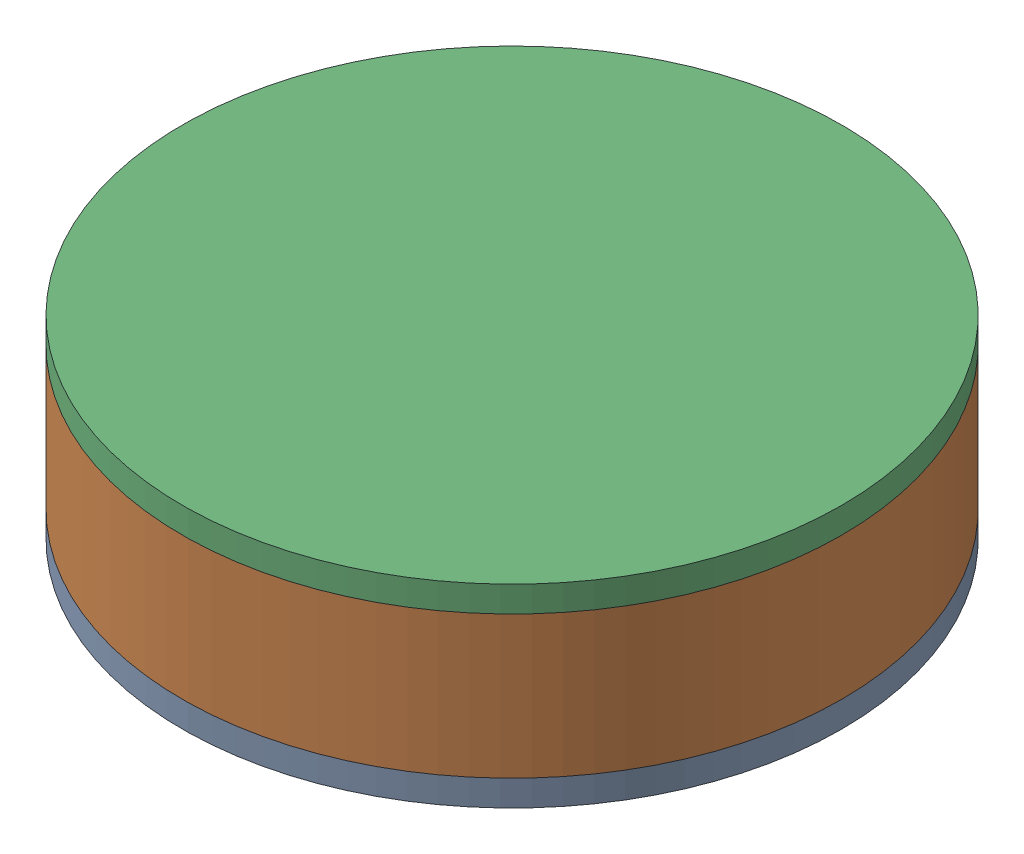
SolidWorks assembly Tip Mass, configuration Default. Lengths in mm.
Overall size (51 15 51).
3 component instances, 3 part files, 4 mates.
Components (placement in the parent):
- Tip Mass Bottom Plate (1)-1: Tip Mass Bottom Plate (1) [Default] at (20.4018 24.2669 38.6628) x (1 0 0) z (0 1 0) size (51 51 4)
- Tip Mass Side Wall (1)-1: Tip Mass Side Wall (1) [Default] at (20.4018 37.2669 38.6628) x (1 0 0) z (0 -1 0) size (51 51 11)
- Tip Mass Top Plate (1)-1: Tip Mass Top Plate (1) [Default] at (20.4018 39.2669 38.6628) x (1 0 0) z (0 -1 0) size (51 51 4)
Mates (geometry in assembly coordinates):
- Coincident1: coincident anti-aligned: plane of Tip Mass Bottom Plate-1 through (20.4018 26.2669 38.6628) normal (0 1 0); plane of Tip Mass Side Wall-1 through (20.4018 26.2669 38.6628) normal (0 -1 0)
- Concentric1: concentric anti-aligned: cylinder of Tip Mass Bottom Plate-1 through (20.4018 28.2669 38.6628) axis (0 -1 0) radius 20.55; cylinder of Tip Mass Side Wall-1 through (20.4018 26.2669 38.6628) axis (0 1 0) radius 20.5
- Coincident2: coincident anti-aligned: plane of Tip Mass Side Wall-1 through (20.4018 37.2669 38.6628) normal (0 1 0); plane of Tip Mass Top Plate-1 through (20.4018 37.2669 38.6628) normal (0 -1 0)
- Concentric2: concentric aligned: cylinder of Tip Mass Side Wall-1 through (20.4018 26.2669 38.6628) axis (0 1 0) radius 20.5; cylinder of Tip Mass Top Plate-1 through (20.4018 35.2669 38.6628) axis (0 1 0) radius 20.55
